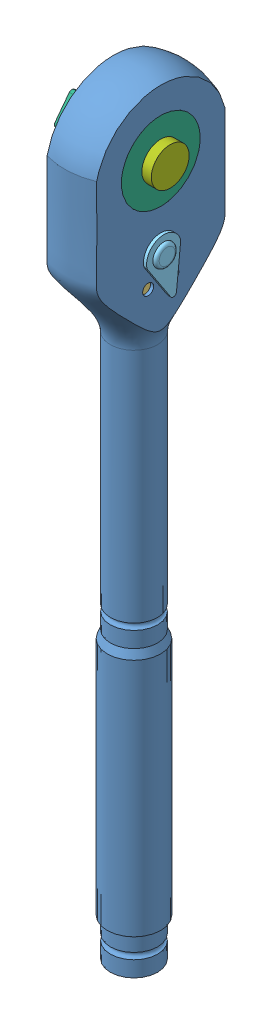
SolidWorks assembly Złożenie1, configuration Default. Lengths in mm.
Overall size (42.41 247.28 47.58).
10 component instances, 9 part files, 23 mates.
Components (placement in the parent):
- Uchwyt-1: Uchwyt [Default] at (74.0288 3.8414 198.5467) size (42.41 246 45.59)
- Lewy-1: Lewy [Default] at (79.5288 194.0352 194.5467) x (0 0.600897 0.799327) z (-1 0 0) size (3.5 21.25 12)
- Prawy-1: Prawy [Default] at (69.5288 194.0352 202.5467) x (0 0.263569 -0.96464) z (1 0 0) size (3.5 21.25 12)
- Część3-1: Część3 [Default] at (79.5288 196.2706 197.1155) x (0 -0.238533 0.971134) z (-1 0 0) size (8.25 8.73 8)
- Część4-1: Część4 [Default] at (82.5288 187.0449 194.8494) x (0 0.238533 -0.971134) z (1 0 0) size (10.99 19.01 12)
- Zebatka-1: Zebatka [3.8 cala] at (70.0288 227.3414 198.5467) x (0 -0.604083 -0.796921) z (1 0 0) size (34 33.92 27.5)
- Część2^Złożenie1-1: Część2^Złożenie1 [Default] at (55.0288 227.3414 198.5467) x (0 0.604083 0.796921) z (-1 0 0) size (12 12 30.5) (virtual)
- Część6^Złożenie1-1: Część6^Złożenie1 [Default] at (67.5288 3.8414 198.5467) x (0 0 1) z (-1 0 0) size (40 54.5 2) (virtual)
- sprezyna-2: sprezyna [Default] at (74.0288 209.8504 189.8591) x (1 0 0) z (0 0.799327 -0.600897) size (6.4 10.4 7.39)
- sprezyna-3: sprezyna [Default] at (74.0288 203.8414 215.2275) x (1 0 0) z (0 0.96464 0.263569) size (6.4 10.4 7.39)
Mates (geometry in assembly coordinates):
- Wspólnie1: coincident aligned: circle of Uchwyt-1; circle of Część3-1
- Wspólnie2: coincident anti-aligned: circle of Uchwyt-1; circle of Prawy-1
- Wspólnie3: coincident aligned: circle of Uchwyt-1; circle of Lewy-1
- Stycznie1: tangent anti-aligned: plane of Prawy-1 through (79.5288 194.4964 200.8585) normal (0 0.263569 -0.96464); cylinder of Część3-1 through (71.5288 197.1945 200.5591) axis (1 0 0) radius 1
- Stycznie2: tangent anti-aligned: plane of Lewy-1 through (69.5288 195.0868 195.9455) normal (0 0.600897 0.799327); cylinder of Część3-1 through (71.5288 198.6848 194.4917) axis (1 0 0) radius 1
- Wspólnie14: coincident anti-aligned: circle of Uchwyt-1; circle of Zebatka-1
- Wspólnie16: coincident aligned: circle of Uchwyt-1; circle of Część4-1
- Równolegle7: parallel anti-aligned: plane of Część3-1 through (79.5288 196.2706 197.1155) normal (0 -0.238533 0.971134); plane of Część4-1 through (82.5288 187.0449 194.8494) normal (0 0.238533 -0.971134)
- Ustalone1: in place: plane of ? through (51.0288 228.3743 193.3341) normal (-1 0 0); plane of ? through (51.0288 0 0) normal (-1 0 0); moOrthogonalPlaneRef_w of ? through (51.0288 228.3743 193.3341) normal (-1 0 0); plane of ? through (51.0288 0 0) normal (0 1 0); plane of ? through (51.0288 228.3743 193.3341) normal (-1 0 0); plane of ? through (51.0288 0 0) normal (0 0 1); plane of Zebatka-1 through (55.0288 232.6057 199.2712) normal (-1 0 0); unknown of Część2^Złożenie1-1
- Wspólnie20: coincident aligned: plane of Zebatka-1; plane of Część2^Złożenie1-1
- Wspólnie21: coincident aligned: moOrthogonalPlaneRef_w of Zebatka-1; plane of Część2^Złożenie1-1 through (55.0288 227.3414 198.5467) normal (0 0.796921 -0.604083)
- Wspólnie22: coincident anti-aligned: moOrthogonalPlaneRef_w of Zebatka-1; plane of Część2^Złożenie1-1 through (55.0288 227.3414 198.5467) normal (0 0.604083 0.796921)
- Ustalone3: in place: plane of Uchwyt-1 through (67.5288 176.8414 176.1643) normal (-1 0 0); plane of ? through (67.5288 0 0) normal (-1 0 0); plane of Uchwyt-1 through (67.5288 176.8414 176.1643) normal (-1 0 0); plane of ? through (67.5288 0 0) normal (0 1 0); plane of Uchwyt-1 through (67.5288 176.8414 176.1643) normal (-1 0 0); plane of ? through (67.5288 0 0) normal (0 0 1); plane of Uchwyt-1 through (67.5288 176.8414 176.1643) normal (-1 0 0); unknown of Część6^Złożenie1-1
- Wspólnie26: coincident aligned: plane of Uchwyt-1; plane of Część6^Złożenie1-1
- Wspólnie27: coincident aligned: moOrthogonalPlaneRef_w of Uchwyt-1 through (67.5288 3.8414 198.5467) normal (0 1 0); plane of Część6^Złożenie1-1 through (67.5288 3.8414 198.5467) normal (0 1 0)
- Wspólnie28: coincident anti-aligned: moOrthogonalPlaneRef_w of Uchwyt-1 through (67.5288 3.8414 198.5467) normal (0 0 -1); plane of Część6^Złożenie1-1 through (67.5288 3.8414 198.5467) normal (0 0 1)
- Limit kąta1: limit planar angle = 0.240855 rad: plane of assembly through (0 0 0) normal (0 0 1); plane of assembly; plane of Część4-1 through (82.5288 187.0449 194.8494) normal (0 0.238533 -0.971134)
- Wspólnie30: coincident: point of Uchwyt-1; point of sprezyna-2
- Równolegle10: parallel aligned: plane of Lewy-1 through (69.5288 208.5705 181.4303) normal (0 -0.600897 -0.799327); plane of sprezyna-2 through (74.0288 209.8504 189.8591) normal (0 -0.600897 -0.799327)
- Równolegle11: parallel aligned: plane of Lewy-1 through (69.5288 208.5705 181.4303) normal (0 0.799327 -0.600897); plane of sprezyna-2 through (74.0288 209.8504 189.8591) normal (0 0.799327 -0.600897)
- Wspólnie34: coincident: unknown of Uchwyt-1; unknown of sprezyna-3
- Równolegle13: parallel aligned: plane of Prawy-1 through (79.5288 212.3844 209.3744) normal (0 0.96464 0.263569); plane of sprezyna-3 through (74.0288 203.8414 215.2275) normal (0 0.96464 0.263569)
- Równolegle14: parallel anti-aligned: plane of Prawy-1 through (79.5288 212.3844 209.3744) normal (0 -0.263569 0.96464); plane of sprezyna-3 through (74.0288 203.8414 215.2275) normal (0 0.263569 -0.96464)
